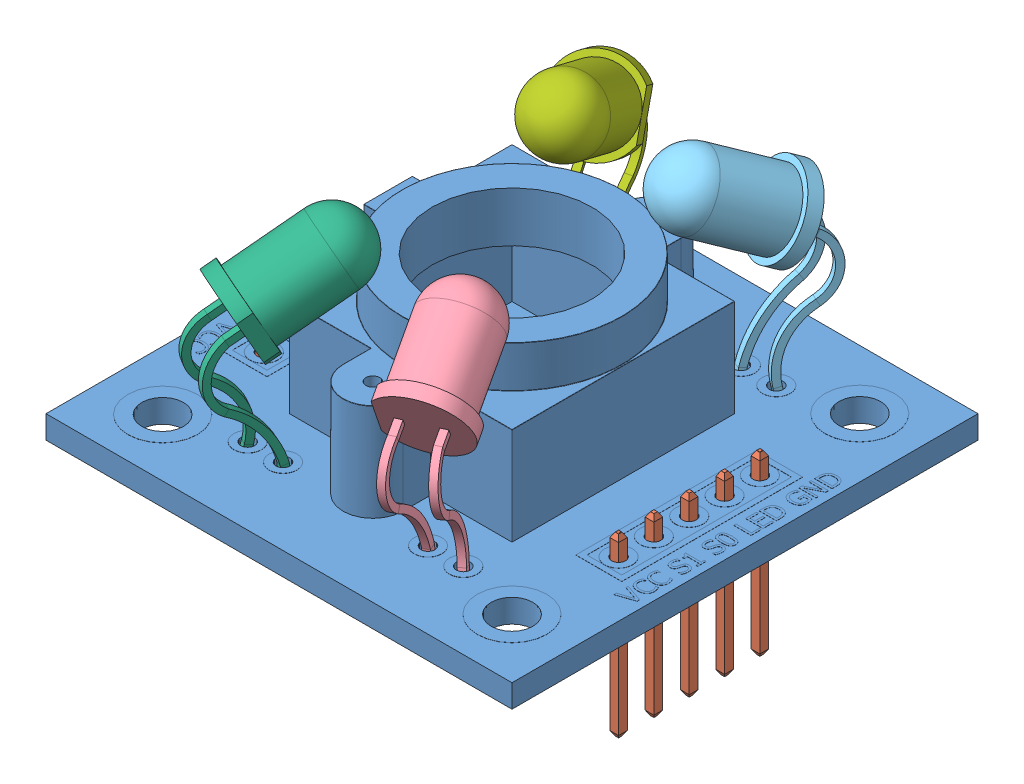
SolidWorks assembly Color_sensor, configuration Default. Lengths in mm.
Overall size (33.5 27.04 39.61).
11 component instances, 8 part files, 0 mates.
Components (placement in the parent):
- Color_sensor.stp-1: Color_sensor.stp [Default] at origin size (33.5 27.04 39.61)
  - Color_sensor_PCB.stp-1: Color_sensor_PCB.stp [Default] at (-4.0861 -1.7155 0) size (33.5 11.66 33.5)
  - Pin Header 1x5 TH Pitch 2.54mm.stp-1: Pin Header 1x5 TH Pitch 2.54mm.stp [Default] at (8.6639 -1.7141 5.09) x (0 0 -1) z (0 -1 0) size (12.7 2.54 12.71)
  - Pin Header 1x5 TH Pitch 2.54mm.stp-2: Pin Header 1x5 TH Pitch 2.54mm.stp [Default] at (-16.8361 -1.7141 5.09) x (0 0 -1) z (0 -1 0) size (12.7 2.54 12.71)
  - TCS3200.stp-1: TCS3200.stp [Default] at (-4.0861 -0.0655 0) size (6.4 1.75 5)
  - 5mm LED.stp-1: 5mm LED.stp [Default] at (2.7257 9.1889 13.2656) x (0.913201 0 -0.407509) z (0.191299 0.882967 0.428689) size (5.45 13.88 15.34)
  - 5mm LED_MIR.stp-1: 5mm LED_MIR.stp [Default] at (2.7257 9.1889 -13.2656) x (0.913201 0 0.407509) z (-0.191299 -0.882967 0.428689) size (5.45 13.88 15.34)
  - 5mm LED_MIR1.stp-1: 5mm LED_MIR1.stp [Default] at (-10.8979 9.1889 13.2656) x (-0.913201 0 -0.407509) z (0.191299 -0.882967 -0.428689) size (5.45 13.88 15.34)
  - 5mm LED_MIR_MIR.stp-1: 5mm LED_MIR_MIR.stp [Default] at (-10.8979 9.1889 -13.2656) x (-0.913201 0 0.407509) z (-0.191299 0.882967 -0.428689) size (5.45 13.88 15.34)
  - Screw GB_T 13806.2 A ST1.5 x 4.stp-1: Screw GB_T 13806.2 A ST1.5 x 4.stp [Default] at (-4.0861 -1.7155 -10) x (0 1 0) z (0 0 1) size (4.89 2.8 2.8)
  - Screw GB_T 13806.2 A ST1.5 x 4.stp-2: Screw GB_T 13806.2 A ST1.5 x 4.stp [Default] at (-4.0861 -1.7155 10) x (0 1 0) z (0 0 1) size (4.89 2.8 2.8)
